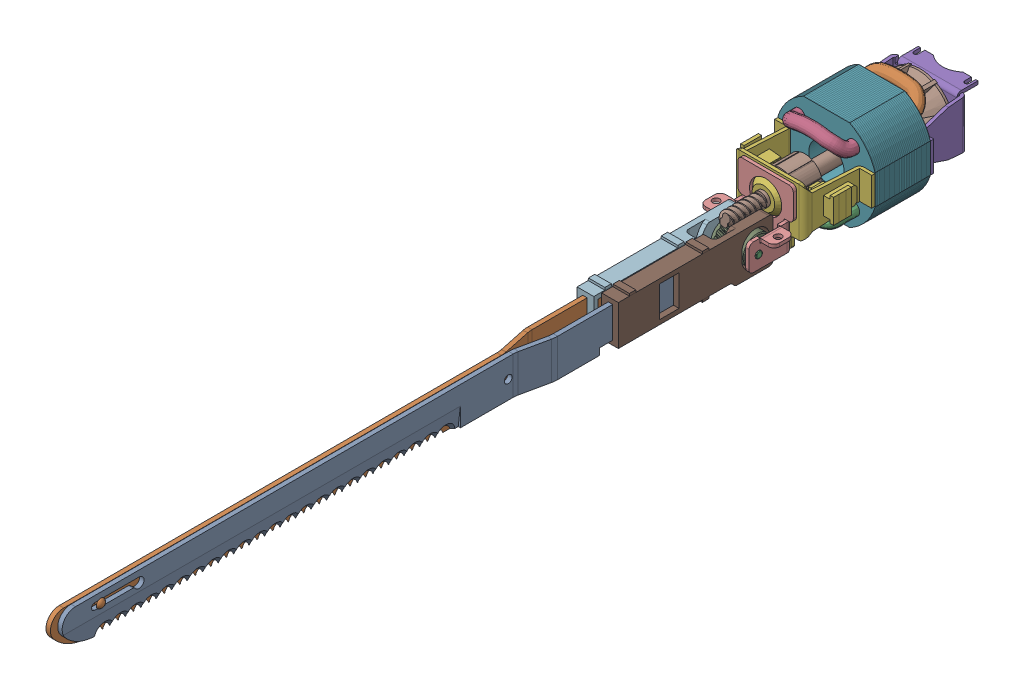
SolidWorks assembly CARVING KNIFE, configuration 02 - Boundary. Lengths in mm.
Overall size (44 41.85 405.71).
11 component instances, 10 part files, 6 mates.
Components (placement in the parent):
- Knife Mechanism-1: Knife Mechanism [Default] at (0 0 -135) size (44 41.85 405.71) (flexible)
  - motor-1: motor [Default] at origin size (44 41 83.5)
  - shaft-1: shaft [Default] at (0 0 53.5) x (0.891785 -0.452459 0) z (0 0 1) size (31.13 31.13 96.88)
  - Gear-1: Gear [Default] at (0 -10.3187 53.7366) x (1 0 0) z (0 0.046429 0.998922) size (17.46 18.38 18.37)
  - Gear Mount-1: Gear Mount [Default] at (0 0 38.5) size (33.55 26.32 19.5)
  - Left Knife Sleeve-1: Left Knife Sleeve [Default] at (5.1912 -10.3187 52.1508) size (7.54 21 70)
  - Right Knife Sleeve-2: Right Knife Sleeve [Default] at (4.8087 -10.3187 55.3224) size (7.54 21 70)
  - Left Blade-1: Left Blade [Default] at (-5.0496 -19.3187 70.3508) x (0 0 -1) z (1 0 0) size (289.69 17 5.12)
  - Right Blade-1: Right Blade [Default] at (-5.1912 -19.3187 73.5224) x (0 0 -1) z (1 0 0) size (289.69 17 8.64)
  - Gear Rod-1: Gear Rod [Default] at (6 -10.3187 53.7366) x (1 0 0) z (0 -0.489933 0.87176) size (23 3.17 3.17)
- Knife Handle-DEMO-1: Knife Handle-DEMO [Default] at origin (suppressed, hidden)
Mates (geometry in assembly coordinates):
- Distance1: distance = 135 mm aligned: plane of Knife Mechanism-1 through (0 0 -135) normal (0 0 1); plane of assembly through (0 0 0) normal (0 0 1)
- Coincident1: coincident aligned: plane of Knife Mechanism-1 through (0 0 -135) normal (0 1 0); plane of assembly through (0 0 0) normal (0 1 0)
- Coincident2: coincident aligned: plane of Knife Mechanism-1 through (0 0 -135) normal (1 0 0); plane of assembly through (0 0 0) normal (1 0 0)
- Coincident3: coincident aligned: plane of knife handle-demo-1 through (0 0 0) normal (0 0 1); plane of assembly through (0 0 0) normal (0 0 1)
- Coincident4: coincident aligned: plane of knife handle-demo-1 through (0 0 0) normal (0 1 0); plane of assembly through (0 0 0) normal (0 1 0)
- Coincident5: coincident aligned: plane of knife handle-demo-1 through (0 0 0) normal (1 0 0); plane of assembly through (0 0 0) normal (1 0 0)
